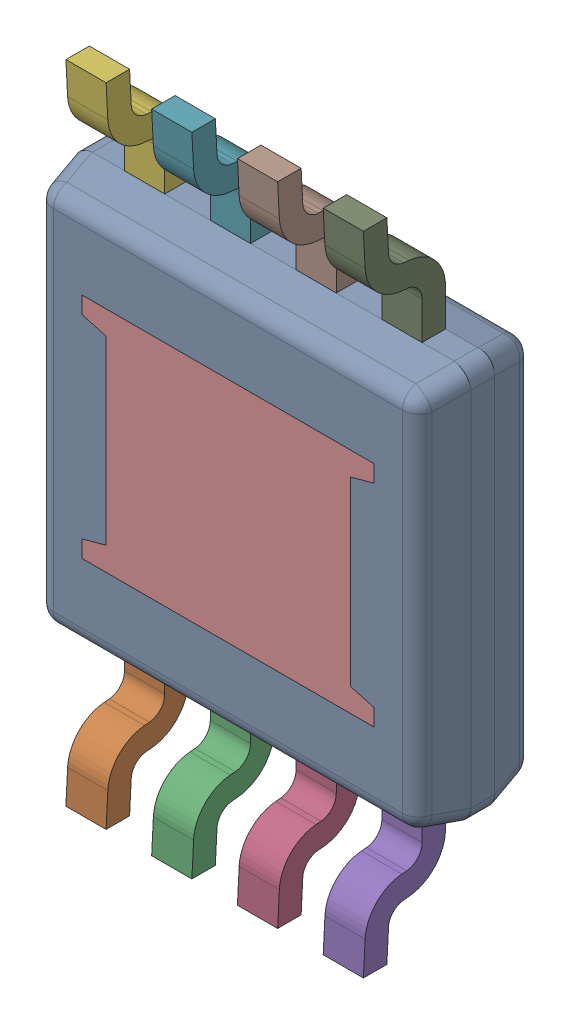
SolidWorks assembly U600_3PCB, configuration Default. Lengths in mm.
Overall size (3 4.9 0.97).
11 component instances, 3 part files, 0 mates.
Components (placement in the parent):
- MUY08A_ASM-1: MUY08A_ASM [Default] at (102.7036 96.0001 -2.2638) x (-1 0 0) z (0 -1 0) size (3 0.97 4.9)
  - BODY_MUY08A-1: BODY_MUY08A [Default] at origin size (3 0.86 3)
  - LEAD_MUY08A-1: LEAD_MUY08A [Default] at (0.9754 -0.3683 1.9177) size (0.31 0.62 0.95)
  - LEAD_MUY08A-2: LEAD_MUY08A [Default] at (0.3251 -0.3683 1.9177) size (0.31 0.62 0.95)
  - LEAD_MUY08A-3: LEAD_MUY08A [Default] at (-0.3251 -0.3683 1.9177) size (0.31 0.62 0.95)
  - LEAD_MUY08A-4: LEAD_MUY08A [Default] at (-0.9754 -0.3683 1.9177) size (0.31 0.62 0.95)
  - LEAD_MUY08A-5: LEAD_MUY08A [Default] at (0.9754 -0.3683 -1.9177) x (-1 0 0) z (0 0 -1) size (0.31 0.62 0.95)
  - LEAD_MUY08A-6: LEAD_MUY08A [Default] at (0.3251 -0.3683 -1.9177) x (-1 0 0) z (0 0 -1) size (0.31 0.62 0.95)
  - LEAD_MUY08A-7: LEAD_MUY08A [Default] at (-0.3251 -0.3683 -1.9177) x (-1 0 0) z (0 0 -1) size (0.31 0.62 0.95)
  - LEAD_MUY08A-8: LEAD_MUY08A [Default] at (-0.9754 -0.3683 -1.9177) x (-1 0 0) z (0 0 -1) size (0.31 0.62 0.95)
  - EXP_PAD_MUY08A-1: EXP_PAD_MUY08A [Default] at (0 -0.3429 0) size (2.21 0.3 1.73)
